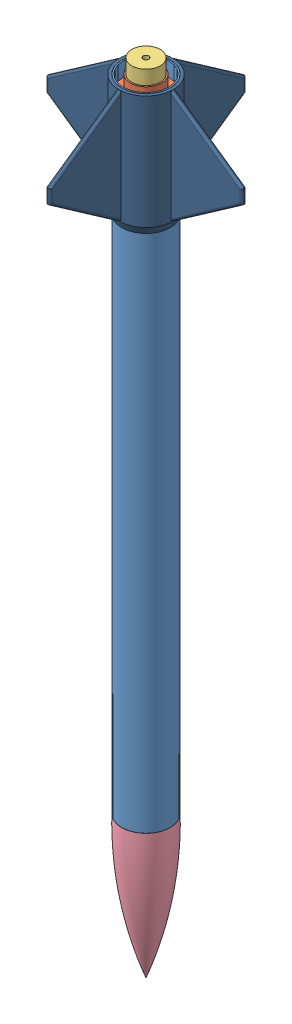
SolidWorks assembly Rocket_Assembly, configuration По умолчанию. Lengths in mm.
Overall size (137.88 560 137.88).
12 component instances, 11 part files, 13 mates.
Components (placement in the parent):
- Body_Tube-1: Body_Tube [По умолчанию] at origin size (34 450 34)
- Motor_Mount_RD-1-20-5-1: Motor_Mount_RD-1-20-5 [По умолчанию] at (0 390 0) size (32 60 32)
- Motor_RD-1-20-5-2: Motor_RD-1-20-5 [По умолчанию] at (0 460 0) x (0.118615 0 -0.99294) z (-0.99294 0 -0.118615) size (20 85 20)
- Nose_Cone-1: Nose_Cone [По умолчанию] at (0 30 0) x (1 0 0) z (0 0 -1) size (34.08 130 34.08)
- Altimeter-1: Altimeter [По умолчанию] at (0 30 0) x (0 0 1) z (1 0 0) size (29.34 56.95 29.63)
  - Altimeter_Mount-1: Altimeter_Mount [По умолчанию] at origin size (28 7 28)
  - STM32L031K6-1: STM32L031K6 [По умолчанию] at (-3.6258 27.2467 0) x (0 -1 0) z (0 0 -1) size (51 14.7 19)
  - Battery_Mount-1: Battery_Mount [По умолчанию] at (0.9801 0 0.0031) x (-0.999752 0 -0.02229) z (-0.02229 0 0.999752) size (28.69 4.5 29)
  - Battery_CR2032-1: Battery_CR2032 [По умолчанию] at (0.3246 -4.7 -0.0115) x (0.225986 0 -0.97413) z (0.97413 0 0.225986) size (20 3.2 20)
  - BMP_280-1: BMP_280 [По умолчанию] at (3.7347 5.9 0) x (0 0 1) z (1 0 0) size (14 10.4 10.5)
- Fins_With_Mount-2: Fins_With_Mount [По умолчанию] at (62.9516 336.7314 -46.5189) x (0 1 0) z (0 0 1) size (85.47 137.88 137.88)
- Parachute_and_rope-1: Parachute_and_rope [По умолчанию] at (0 45 0) size (32 35 32)
Mates (geometry in assembly coordinates):
- Концентричный1: concentric anti-aligned: cylinder of Body_Tube-1 through (0 450 0) axis (0 -1 0) radius 16; cylinder of Motor_Mount_RD-1-20-5-1 through (0 438 0) axis (0 1 0) radius 16
- Совпадение1: coincident aligned: plane of Body_Tube-1 through (0 450 0) normal (0 1 0); plane of Motor_Mount_RD-1-20-5-1 through (0 450 0) normal (0 1 0)
- Совпадение3: coordinate: point of Body_Tube-1; point of assembly
- Концентричный3: concentric anti-aligned: cylinder of Body_Tube-1 through (0 450 0) axis (0 -1 0) radius 16; cylinder of Nose_Cone-1 through (0 0 0) axis (0 1 0) radius 16
- Совпадение4: coincident anti-aligned: plane of Body_Tube-1 through (0 0 0) normal (0 -1 0); plane of Nose_Cone-1 through (0 0 0) normal (0 1 0)
- Концентричный7: concentric anti-aligned: cylinder of Body_Tube-1 through (0 450 0) axis (0 -1 0) radius 17; cylinder of ? through (0 370 0) axis (0 1 0) radius 17
- Концентричный8: concentric: cylinder of Nose_Cone-1 through (0 0 0) axis (0 1 0) radius 15; cylinder of Altimeter-1/Altimeter_Mount-1 through (0 23 0) axis (0 1 0) radius 14
- Концентричный9: concentric anti-aligned: cylinder of Body_Tube-1 through (0 450 0) axis (0 -1 0) radius 17; cylinder of Fins_With_Mount-2 through (0 370 0) axis (0 1 0) radius 17
- Совпадение10: coincident aligned: plane of Body_Tube-1 through (0 450 0) normal (0 1 0); plane of Fins_With_Mount-2 through (0 450 0) normal (0 1 0)
- Концентричный10: concentric aligned: cylinder of Body_Tube-1 through (0 450 0) axis (0 -1 0) radius 16; cylinder of Parachute_and_rope-1 through (0 80 0) axis (0 -1 0) radius 16
- Концентричный12: concentric: cylinder of Nose_Cone-1 through (0 27.5 17.0415) axis (0 0 -1) radius 0.8; cylinder of Altimeter-1/Altimeter_Mount-1 through (0 27.5 0.2373) axis (0 0 1) radius 0.8
- Совпадение12: coincident: unknown of Altimeter-1/Altimeter_Mount-1
- Совпадение13: coincident: unknown of Altimeter-1/Altimeter_Mount-1
